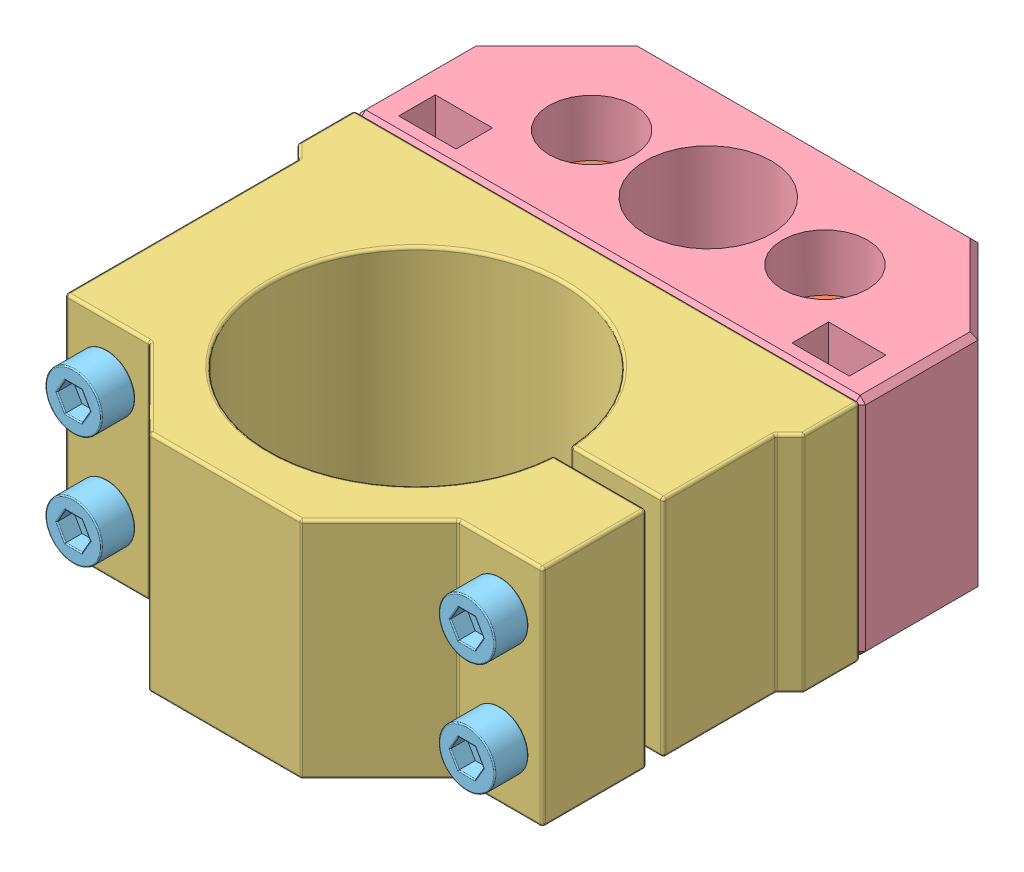
SolidWorks assembly Spindle_assembly, configuration Default. Lengths in mm.
Overall size (90 40 104).
9 component instances, 5 part files, 0 mates.
Components (placement in the parent):
- TR8_lead_screw-1: TR8_lead_screw [Default] at (0 3.5 0) x (1 0 0) z (0 1 0) size (22 22 16.4)
- LM8_20mm-3: LM8_20mm [Default] at (-20.75 0 0) x (1 0 0) z (0 -1 0) size (15 15 20)
- LM8_20mm-4: LM8_20mm [Default] at (20.75 0 0) x (1 0 0) z (0 -1 0) size (15 15 20)
- Spindle_mount-1: Spindle_mount [Default] at (0 0 52) x (1 0 0) z (0 -1 0) size (90 68 40)
- Tool_mount-1: Tool_mount [Default] at origin size (90 40 36)
- M6x60-1: M6x60 [Default] at (-35 10 72) x (1 0 0) z (0 -1 0) size (10 66 10)
- M6x60-5: M6x60 [Default] at (-35 -10 72) x (1 0 0) z (0 -1 0) size (10 66 10)
- M6x60-6: M6x60 [Default] at (35 10 72) x (1 0 0) z (0 -1 0) size (10 66 10)
- M6x60-7: M6x60 [Default] at (35 -10 72) x (1 0 0) z (0 -1 0) size (10 66 10)
